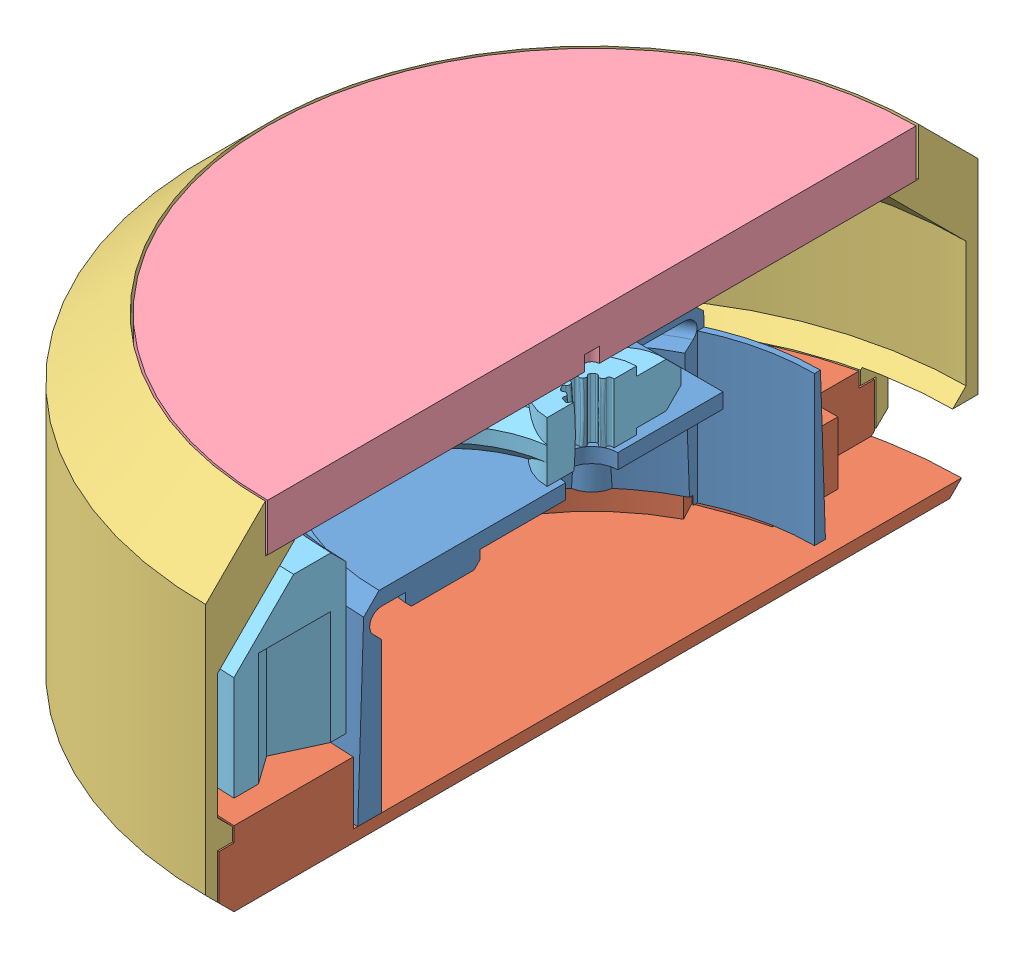
SolidWorks assembly 0.ASM, configuration Default. Lengths in mm.
Overall size (40.85 22.8 55.11).
5 component instances, 5 part files, 9 mates.
Components (placement in the parent):
- base-1: base [Default] at (9.8039 11.1073 24.2675) size (31.4 13 31.37)
- base2-1: base2 [Default] at (9.8049 10.3073 24.2664) x (-1 0 0) z (0 0 -1) size (50 5 49.8)
- base3-1: base3 [Default] at (9.8049 15.3073 24.2664) size (51.8 21.7 51.8)
- glass-1: glass [Default] at (9.8049 29.9073 24.2664) size (43.5 3.17 43.5)
- arm-1: arm [Default] at (9.8039 24.5073 24.2675) x (-0.733611 0 0.67957) z (-0.67957 0 -0.733611) size (29.15 11.6 29.56)
Mates (geometry in assembly coordinates):
- Coincident1: coincident anti-aligned: plane of base-1 through (-5.8961 11.1073 24.2675) normal (0 -1 0); plane of base2-1 through (9.8049 11.1073 24.2664) normal (0 1 0)
- Concentric1: concentric anti-aligned: circle of base-1; circle of base2-1
- Concentric2: concentric: circle of base-1; circle of base2-1
- Concentric3: concentric anti-aligned: cylinder of base2-1 through (34.8049 13.3073 24.2664) axis (-1 0 0) radius 1.05; cylinder of base3-1 through (-16.0951 13.3073 24.2664) axis (1 0 0) radius 1.05
- Concentric4: concentric anti-aligned: circle of base2-1; circle of base3-1
- Coincident2: coincident anti-aligned: plane of base3-1 through (31.7049 29.9073 24.2664) normal (0 1 0); plane of glass-1 through (9.8049 29.9073 24.2664) normal (0 -1 0)
- Concentric5: concentric anti-aligned: circle of base3-1; circle of glass-1
- Concentric6: concentric aligned: circle of base-1; circle of arm-1
- Distance1: distance = 0.4 mm anti-aligned: plane of base-1 through (9.8039 24.1073 24.2675) normal (0 1 0); plane of arm-1 through (9.8039 24.5073 24.2675) normal (0 -1 0)
